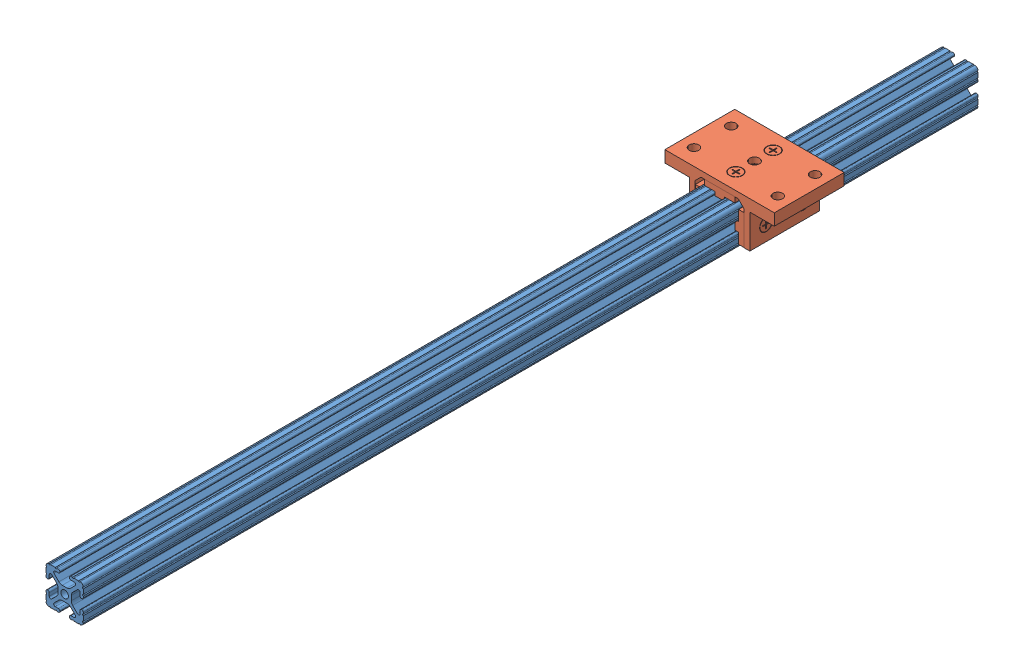
SolidWorks assembly SlidingRail, configuration Default. Lengths in mm.
Overall size (74.57 33.32 609.6).
2 component instances, 2 part files, 2 mates.
Components (placement in the parent):
- ST_T-Slot_Rails-1: ST_T-Slot_Rails [2'] at (-57.4202 18.7462 17.5639) size (25.4 25.4 609.6)
- ST_Track_Slider-1: ST_Track_Slider [47065T959] at (-57.4202 8.4338 -147.6699) size (74.57 30.94 47.62)
Mates (geometry in assembly coordinates):
- Coincident9: coincident aligned: plane of ST_T-Slot_Rails-1 through (-57.4202 18.7462 17.5639) normal (1 0 0); plane of ST_Track_Slider-1 through (-57.4202 8.4338 -147.6699) normal (1 0 0)
- Coincident10: coincident: plane of ST_T-Slot_Rails-1 through (-57.4202 18.7462 17.5639) normal (0 1 0); line of ST_Track_Slider-1 through (-67.7326 18.7462 -144.4949) axis (0.709069 0 0.705139)
